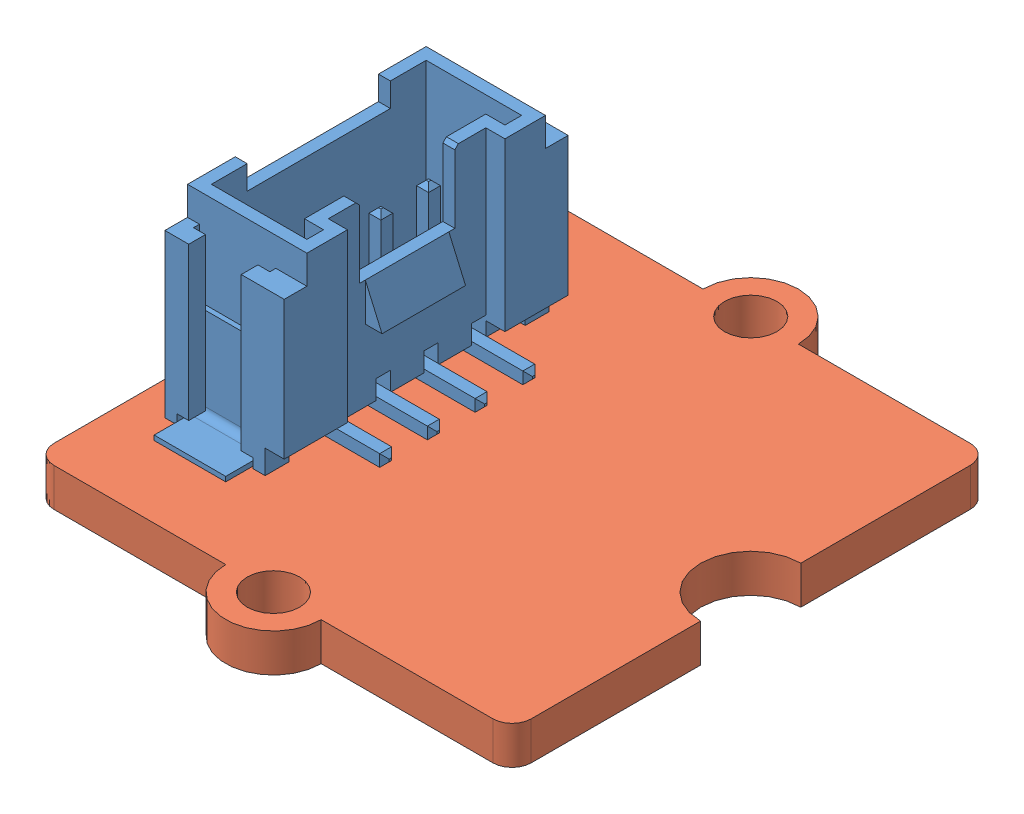
SolidWorks assembly PCB Grove 20x20 SMD Vertical - Temperature v1.2, configuration Défaut. Lengths in mm.
Overall size (20 9.6 24).
2 component instances, 2 part files, 3 mates.
Components (placement in the parent):
- Connector Grove SMD Vertical-1: Connector Grove SMD Vertical [Défaut] at (-4.1217 4.697 23.9799) x (0 0 -1) z (1 0 0) size (14 8 6.5)
- PCB Grove 20x20 - Temprature v1.2-1: PCB Grove 20x20 - Temprature v1.2 [Défaut] at (-0.5217 3.897 23.9799) size (20 1.6 24)
Mates (geometry in assembly coordinates):
- Coïncidente1: coincident anti-aligned: plane of Connector Grove SMD Vertical-1 through (-3.0635 4.697 23.9799) normal (0 0 -1); plane of PCB Grove 20x20 - Grove Temprature v1.2-1 through (-0.5217 3.897 23.9799) normal (0 0 1)
- Coïncidente2: coincident anti-aligned: plane of Connector Grove SMD Vertical-1 through (-7.4635 4.697 18.4799) normal (0 -1 0); plane of PCB Grove 20x20 - Grove Temprature v1.2-1 through (-0.5217 4.697 23.9799) normal (0 1 0)
- Distance1: distance = 1.4 mm aligned: plane of Connector Grove SMD Vertical-1 through (-9.1217 12.697 28.9799) normal (-1 0 0); plane of PCB Grove 20x20 - Grove Temprature v1.2-1 through (-10.5217 4.697 23.9799) normal (-1 0 0)
